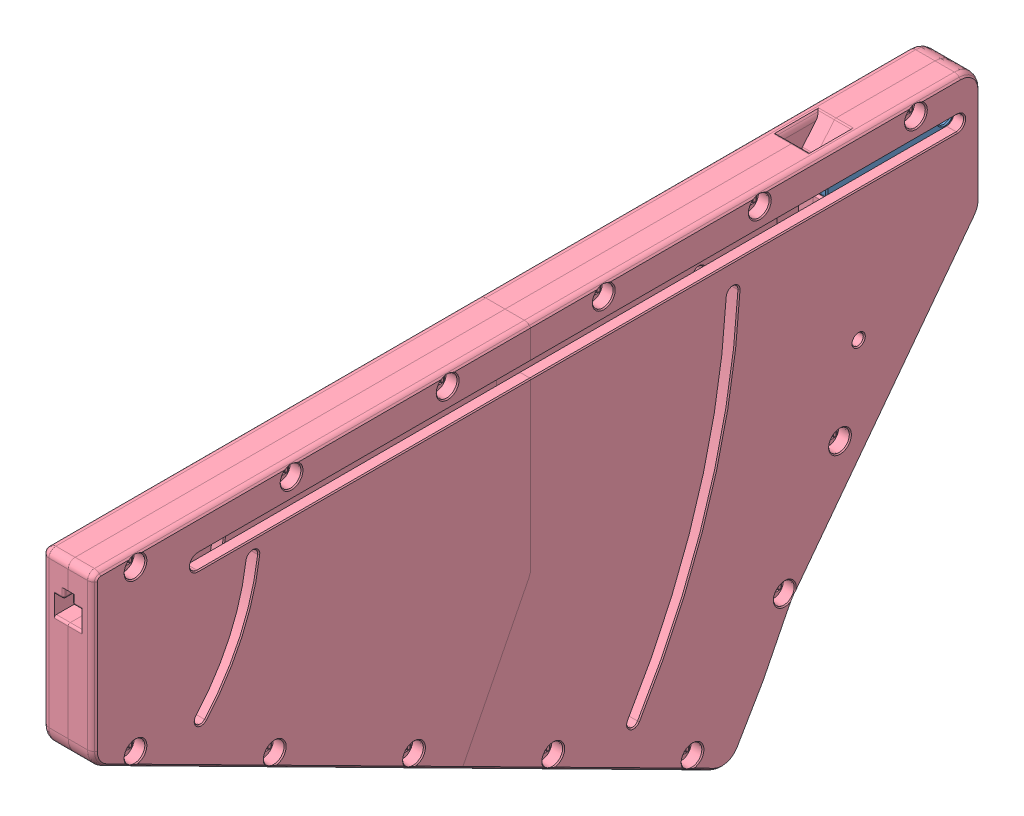
SolidWorks assembly Magazine, configuration Default. Lengths in mm.
Overall size (15.11 138.95 255.9).
4 component instances, 4 part files, 16 mates.
Components (placement in the parent):
- Pusher^Magazine-1: Pusher^Magazine [Default] at origin size (7.6 8.4 40) (virtual)
- Blocker^Magazine-1: Blocker^Magazine [Default] at origin size (7.6 50.79 33.84) (virtual)
- Follower^Magazine-1: Follower^Magazine [Default] at origin size (7.6 97.92 181.62) (virtual)
- Casing^Magazine-1: Casing^Magazine [Default] at origin size (15.11 138.95 255.9) (virtual)
Mates (geometry in assembly coordinates):
- InPlace1: in place: plane of ? through (0 0 0) normal (0 0 1); moOrthogonalPlaneRef_w of ? through (0 0 0) normal (0 1 0); plane of ? through (0 0 0) normal (1 0 0); unknown of ?
- Coincident1: coincident aligned: 
- Coincident2: coincident aligned: plane of Pusher^Magazine-1 through (0 0 0) normal (0 1 0)
- Coincident3: coincident anti-aligned: plane of Pusher^Magazine-1 through (0 0 0) normal (1 0 0)
- InPlace2: in place: plane of ? through (0 0 0) normal (0 0 1); plane of ? through (0 0 0) normal (0 1 0); plane of ? through (0 0 0) normal (1 0 0); unknown of ?
- Coincident4: coincident aligned: 
- Coincident5: coincident aligned: plane of Blocker^Magazine-1 through (0 0 0) normal (0 1 0)
- Coincident6: coincident anti-aligned: plane of Blocker^Magazine-1 through (0 0 0) normal (1 0 0)
- InPlace3: in place: plane of ? through (0 0 0) normal (0 0 1); plane of ? through (0 0 0) normal (0 1 0); plane of ? through (0 0 0) normal (1 0 0); unknown of ?
- Coincident7: coincident aligned: 
- Coincident8: coincident aligned: plane of Follower^Magazine-1 through (0 0 0) normal (0 1 0)
- Coincident9: coincident anti-aligned: plane of Follower^Magazine-1 through (0 0 0) normal (1 0 0)
- InPlace4: in place: plane of ? through (0 0 0) normal (0 0 1); plane of ? through (0 0 0) normal (0 1 0); plane of ? through (0 0 0) normal (1 0 0); unknown of ?
- Coincident10: coincident aligned: 
- Coincident11: coincident aligned: plane of Casing^Magazine-1 through (0 0 0) normal (0 1 0)
- Coincident12: coincident anti-aligned: plane of Casing^Magazine-1 through (0 0 0) normal (1 0 0)
